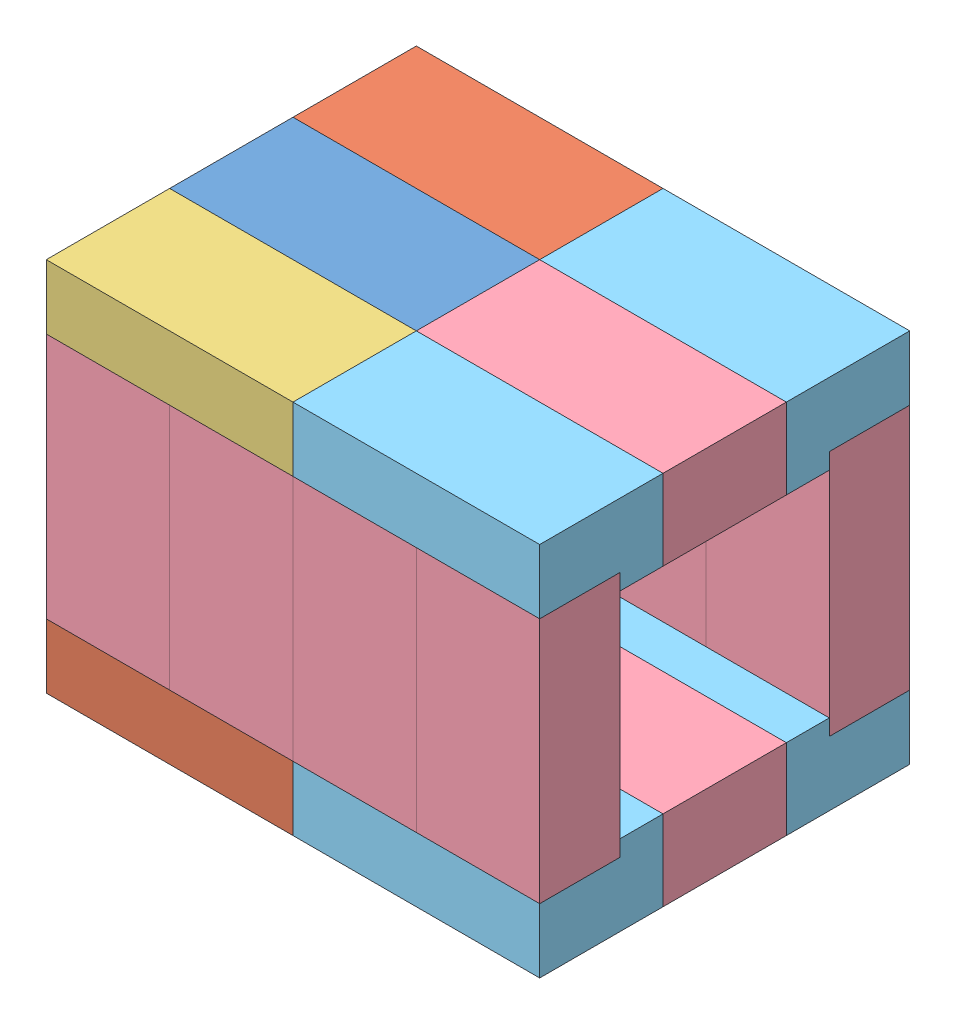
SolidWorks assembly Assem3, configuration Default. Lengths in mm.
Overall size (465.32 350 353.06).
27 component instances, 6 part files, 10 mates.
Components (placement in the parent):
- Heat Treat Asm Top-Bot Alt-1: Heat Treat Asm Top-Bot Alt [Default] at origin size (460 75 345)
  - Brick-Sharp-BackCut-1: Brick-Sharp-BackCut [Default] at (64.2972 119.1646 188.5049) size (230 75 115)
  - Brick-Sharp-BackLeftCut-1: Brick-Sharp-BackLeftCut [Default] at (64.2972 119.1646 303.5049) size (230 75 115)
  - Brick-Sharp-BackRightCut-1: Brick-Sharp-BackRightCut [Default] at (64.2972 119.1646 73.5049) size (230 75 115)
  - Brick-Sharp-2: Brick-Sharp [Default] at (294.2972 119.1646 188.5049) size (230 75 115)
  - Brick-Sharp-SideCut-1: Brick-Sharp-SideCut [Default] at (294.2972 119.1646 73.5049) size (230 75 115)
  - Brick-Sharp-SideCut-2: Brick-Sharp-SideCut [Default] at (294.2972 119.1646 303.5049) x (-1 0 0) z (0 0 -1) size (230 75 115)
- Heat Treat Asm Back-1: Heat Treat Asm Back [Default] at (-81.9509 131.5315 152.0005) x (0.999924 0.008727 0.008726) z (-0.008727 0 0.999962) size (462.63 234.01 79.01)
  - Brick-Sharp-1: Brick-Sharp [Default] at (91.3299 124.3408 170.7235) x (-0.008727 -0.999962 0) z (-0.999924 0.008726 0.008727) size (230 75 115)
  - Brick-Sharp-2: Brick-Sharp [Default] at (206.3211 123.3373 169.7199) x (0.008727 0.999962 0) z (-0.999924 0.008726 0.008727) size (230 75 115)
  - Brick-Sharp-3: Brick-Sharp [Default] at (436.3036 121.3303 167.7128) x (-0.008727 -0.999962 0) z (0.999924 -0.008726 -0.008727) size (230 75 115)
  - Brick-Sharp-4: Brick-Sharp [Default] at (321.3124 122.3338 168.7164) x (-0.008727 -0.999962 0) z (0.999924 -0.008726 -0.008727) size (230 75 115)
- Heat Treat Asm Back-2: Heat Treat Asm Back [Default] at (-81.9509 131.5315 -117.9995) x (0.999924 0.008727 0.008726) z (-0.008727 0 0.999962) size (462.63 234.01 79.01)
  - Brick-Sharp-1: Brick-Sharp [Default] at (91.3299 124.3408 170.7235) x (-0.008727 -0.999962 0) z (-0.999924 0.008726 0.008727) size (230 75 115)
  - Brick-Sharp-2: Brick-Sharp [Default] at (206.3211 123.3373 169.7199) x (0.008727 0.999962 0) z (-0.999924 0.008726 0.008727) size (230 75 115)
  - Brick-Sharp-3: Brick-Sharp [Default] at (436.3036 121.3303 167.7128) x (-0.008727 -0.999962 0) z (0.999924 -0.008726 -0.008727) size (230 75 115)
  - Brick-Sharp-4: Brick-Sharp [Default] at (321.3124 122.3338 168.7164) x (-0.008727 -0.999962 0) z (0.999924 -0.008726 -0.008727) size (230 75 115)
- Heat Treat Asm Back Alt-1: Heat Treat Asm Back Alt [Default] at (-141.7788 336.7727 54.7371) x (0 -1 0) z (0 0 1) size (230 75 195)
  - Brick-Sharp-1: Brick-Sharp [Default] at (80.1081 128.5759 173.7678) size (230 75 115)
  - Brick-Sharp-Trimmed-1: Brick-Sharp-Trimmed [Default] at (80.1081 128.5759 58.7678) size (230 75 80)
- Heat Treat Asm Top-Bot Alt-2: Heat Treat Asm Top-Bot Alt [Default] at (0 513.3292 377.0098) x (1 0 0) z (0 0 -1) size (460 75 345)
  - Brick-Sharp-BackCut-1: Brick-Sharp-BackCut [Default] at (64.2972 119.1646 188.5049) size (230 75 115)
  - Brick-Sharp-BackLeftCut-1: Brick-Sharp-BackLeftCut [Default] at (64.2972 119.1646 303.5049) size (230 75 115)
  - Brick-Sharp-BackRightCut-1: Brick-Sharp-BackRightCut [Default] at (64.2972 119.1646 73.5049) size (230 75 115)
  - Brick-Sharp-2: Brick-Sharp [Default] at (294.2972 119.1646 188.5049) size (230 75 115)
  - Brick-Sharp-SideCut-1: Brick-Sharp-SideCut [Default] at (294.2972 119.1646 73.5049) size (230 75 115)
  - Brick-Sharp-SideCut-2: Brick-Sharp-SideCut [Default] at (294.2972 119.1646 303.5049) x (-1 0 0) z (0 0 -1) size (230 75 115)
Mates (geometry in assembly coordinates):
- Coincident1: coincident aligned: line of Heat Treat Asm Top-Bot Alt-1/Brick-Sharp-BackLeftCut-1 through (-50.7028 141.6646 361.0049) axis (1 0 0); line of Heat Treat Asm Back-1/Brick-Sharp-1 through (-50.7028 141.6646 361.0049) axis (1 0 0)
- Coincident2: coincident anti-aligned: line of Heat Treat Asm Top-Bot Alt-1/Brick-Sharp-BackLeftCut-1 through (-50.7028 141.6646 246.0049) axis (0 0 1); line of Heat Treat Asm Back-1/Brick-Sharp-1 through (-50.7028 141.6646 361.0049) axis (0 0 -1)
- Coincident3: coincident anti-aligned: line of Heat Treat Asm Top-Bot Alt-1/Brick-Sharp-SideCut-1 through (409.2972 141.6646 91.0049) axis (0 0 -1); line of Heat Treat Asm Back-2/Brick-Sharp-3 through (409.2972 141.6646 16.0049) axis (0 0 1)
- Coincident4: coincident anti-aligned: line of Heat Treat Asm Top-Bot Alt-1/Brick-Sharp-BackRightCut-1 through (179.2972 141.6646 16.0049) axis (-1 0 0); line of Heat Treat Asm Back-2/Brick-Sharp-1 through (-50.7028 141.6646 16.0049) axis (1 0 0)
- Coincident8: coincident: plane of Heat Treat Asm Top-Bot Alt-1/Brick-Sharp-BackCut-1 through (64.2972 141.6646 188.5049) normal (0 1 0); plane of Heat Treat Asm Back Alt-1/Brick-Sharp-1 through (24.2972 141.6646 171.0049) normal (0 -1 0)
- Coincident9: coincident: line of Heat Treat Asm Top-Bot Alt-1/Brick-Sharp-BackCut-1 through (-50.7028 141.6646 131.0049) axis (0 0 1); line of Heat Treat Asm Back Alt-1/Brick-Sharp-1 through (-50.7028 141.6646 286.0049) axis (0 0 -1)
- Coincident10: coincident anti-aligned: plane of Heat Treat Asm Back-2/Brick-Sharp-1 through (6.7972 256.6646 91.0049) normal (0 0 1); plane of Heat Treat Asm Back Alt-1/Brick-Sharp-Trimmed-1 through (-13.2028 256.6646 91.0049) normal (0 0 -1)
- Coincident11: coincident: plane of Heat Treat Asm Back Alt-1/Brick-Sharp-1 through (24.2972 371.6646 171.0049) normal (0 1 0); plane of Heat Treat Asm Top-Bot Alt-2/Brick-Sharp-BackCut-1 through (64.2972 371.6646 188.5049) normal (0 -1 0)
- Coincident12: coincident: line of Heat Treat Asm Back-1/Brick-Sharp-3 through (409.2972 371.6646 286.0049) axis (0 0 1); line of Heat Treat Asm Top-Bot Alt-2/Brick-Sharp-SideCut-1 through (409.2972 371.6646 286.0049) axis (0 0 1)
- Coincident13: coincident aligned: line of Heat Treat Asm Back-2/Brick-Sharp-4 through (179.2972 371.6646 16.0049) axis (1 0 0); line of Heat Treat Asm Top-Bot Alt-2/Brick-Sharp-SideCut-2 through (179.2972 371.6646 16.0049) axis (1 0 0)
